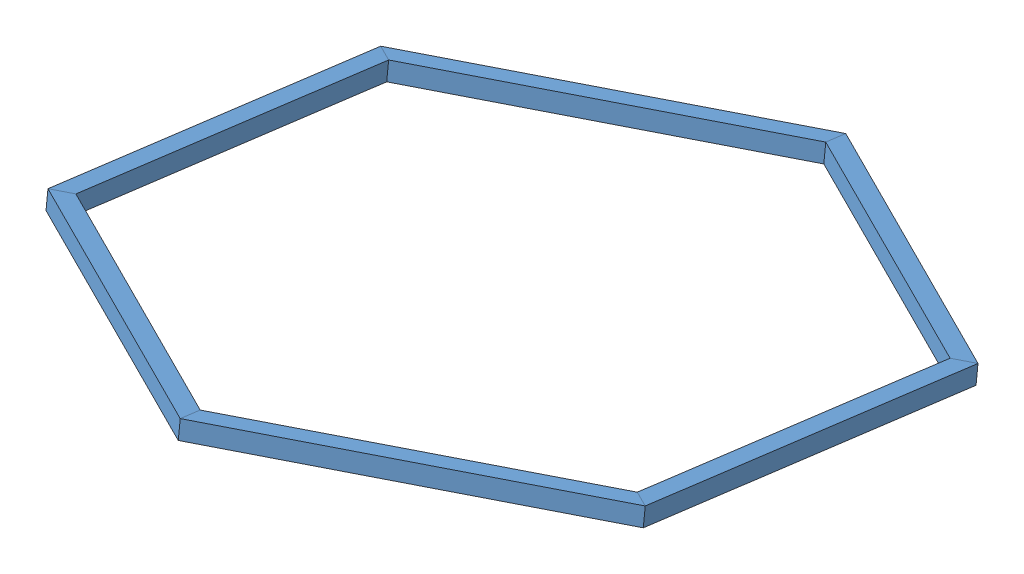
SolidWorks assembly Assem1, configuration Default. Lengths in mm.
Overall size (436.02 81.74 496.99).
6 component instances, 1 part files, 15 mates.
Components (placement in the parent):
- channel-1: channel [Default] at (97.6249 257.2442 21.5553) x (0.999561 0.025522 -0.015028) z (0.027347 -0.99014 0.137388) size (13 250 13)
- channel-2: channel [Default] at (97.3507 290.8712 263.9553) x (0.489931 -0.106524 -0.865228) z (0.027347 -0.99014 0.137388) size (13 250 13)
- channel-5: channel [Default] at (309.6177 246.2041 -100.2059) x (0.50963 0.132047 0.850201) z (0.027347 -0.99014 0.137388) size (13 250 13)
- channel-6: channel [Default] at (524.0606 301.706 257.5484) x (-0.50963 -0.132047 -0.850201) z (-0.027347 0.99014 -0.137388) size (13 250 13)
- channel-7: channel [Default] at (521.062 302.4181 262.8328) x (-0.999561 -0.025522 0.015028) z (0.027347 -0.99014 0.137388) size (13 250 13)
- channel-8: channel [Default] at (521.3362 268.7911 20.4328) x (-0.489931 0.106524 0.865228) z (0.027347 -0.99014 0.137388) size (13 250 13)
Mates (geometry in assembly coordinates):
- Coincident9: coincident: plane of channel-1 through (206.2274 291.8349 202.1399) normal (0.50963 0.132047 0.850201); plane of channel-2 through (98.7325 297.6807 265.6669) normal (-0.50963 -0.132047 -0.850201)
- Coincident11: coincident: line of channel-1 through (94.5323 285.0567 270.1453) axis (0.859959 -0.046767 -0.508216); line of channel-2 through (94.5323 285.0567 270.1453) axis (0.859959 -0.046767 -0.508216)
- Coincident12: coincident: line of channel-1 through (94.1768 297.9285 268.3592) axis (0.027347 -0.99014 0.137388); line of channel-2 through (94.1768 297.9285 268.3592) axis (0.027347 -0.99014 0.137388)
- Coincident14: coincident: plane of channel-1 through (95.9495 263.9756 23.3129) normal (0.489931 -0.106524 -0.865228); plane of channel-5 through (204.866 275.3472 83.5863) normal (-0.489931 0.106524 0.865228)
- Coincident15: coincident: line of channel-1 through (91.3335 263.4937 20.7584) axis (0.027347 -0.99014 0.137388); line of channel-5 through (91.3335 263.4937 20.7584) axis (0.027347 -0.99014 0.137388)
- Coincident16: coincident: line of channel-1 through (91.3335 263.4937 20.7584) axis (0.871332 0.090972 0.482187); line of channel-5 through (91.3335 263.4937 20.7584) axis (0.871332 0.090972 0.482187)
- Coincident17: coincident: plane of channel-2 through (310.5279 302.7245 259.8588) normal (0.999561 0.025522 -0.015028); plane of channel-6 through (310.8834 289.8527 261.6449) normal (-0.999561 -0.025522 0.015028)
- Coincident18: coincident: line of channel-2 through (312.3653 307.7997 390.6921) axis (-0.011373 -0.137739 -0.990403); line of channel-6 through (312.3653 307.7997 390.6921) axis (-0.011373 -0.137739 -0.990403)
- Coincident19: coincident: plane of channel-2 through (312.0098 320.6716 388.906) normal (-0.489931 0.106524 0.865228); line of channel-6 through (312.3653 307.7997 390.6921) axis (-0.027347 0.99014 -0.137388)
- Coincident32: coincident: plane of channel-6 through (522.739 295.6261 261.0836) normal (0.489931 -0.106524 -0.865228); plane of channel-7 through (522.3835 308.4979 259.2976) normal (-0.489931 0.106524 0.865228)
- Coincident33: coincident: line of channel-6 through (527.355 296.1081 263.6381) axis (-0.871332 -0.090972 -0.482187); line of channel-7 through (527.355 296.1081 263.6381) axis (-0.871332 -0.090972 -0.482187)
- Coincident34: coincident: line of channel-6 through (527.355 296.1081 263.6381) axis (-0.027347 0.99014 -0.137388); line of channel-7 through (526.9995 308.9799 261.852) axis (0.027347 -0.99014 0.137388)
- Coincident35: coincident: plane of channel-5 through (306.3835 252.5317 -101.0488) normal (0.999561 0.025522 -0.015028); plane of channel-8 through (307.8051 269.7491 22.7516) normal (-0.999561 -0.025522 0.015028)
- Coincident36: coincident: line of channel-5 through (306.3233 251.802 -106.2956) axis (0.027347 -0.99014 0.137388); line of channel-8 through (306.3233 251.802 -106.2956) axis (0.027347 -0.99014 0.137388)
- Coincident37: coincident: plane of channel-5 through (91.3335 263.4937 20.7584) normal (-0.027347 0.99014 -0.137388); line of channel-8 through (306.3233 251.802 -106.2956) axis (0.011373 0.137739 0.990403)
